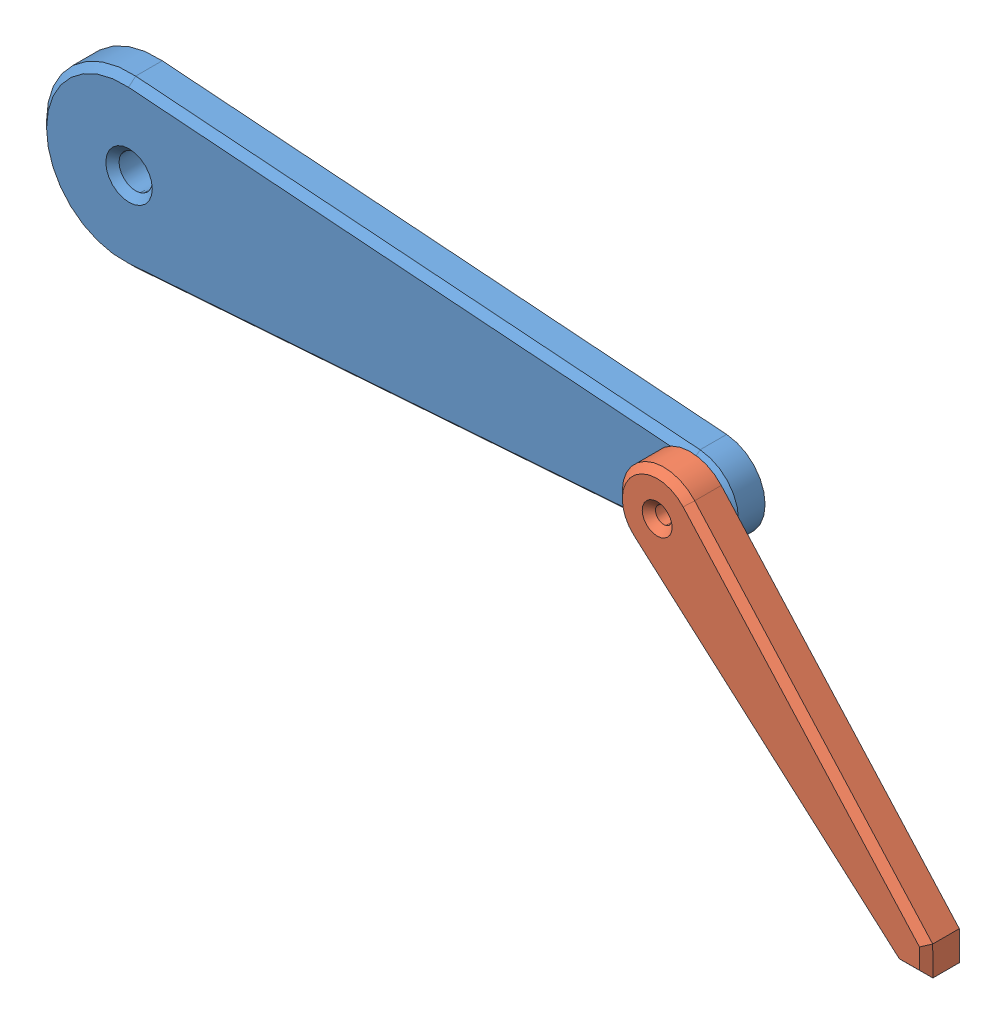
SolidWorks assembly 1PUMA, configuration Default. Lengths in mm.
Overall size (285.63 114.1 20).
2 component instances, 2 part files, 2 mates.
Components (placement in the parent):
- 1Elbow-2: 1Elbow [Default] at (-8.5718 113.102 -29.2376) size (208.33 50 10)
- 1Wrist-1: 1Wrist [Default] at (160.4282 113.102 -19.2376) x (0.710527 -0.70367 0) z (0 0 1) size (126.5 25 10)
Mates (geometry in assembly coordinates):
- Concentric12: concentric: cylinder of ? through (169 116.996 -30) axis (0 0 -1) radius 2.5; cylinder of ? through (169 116.996 -20) axis (0 0 -1) radius 2.5
- Coincident19: coincident: plane of ? through (169 116.996 -30) normal (0 0 1); plane of ? through (169 116.996 -30) normal (0 0 -1)
